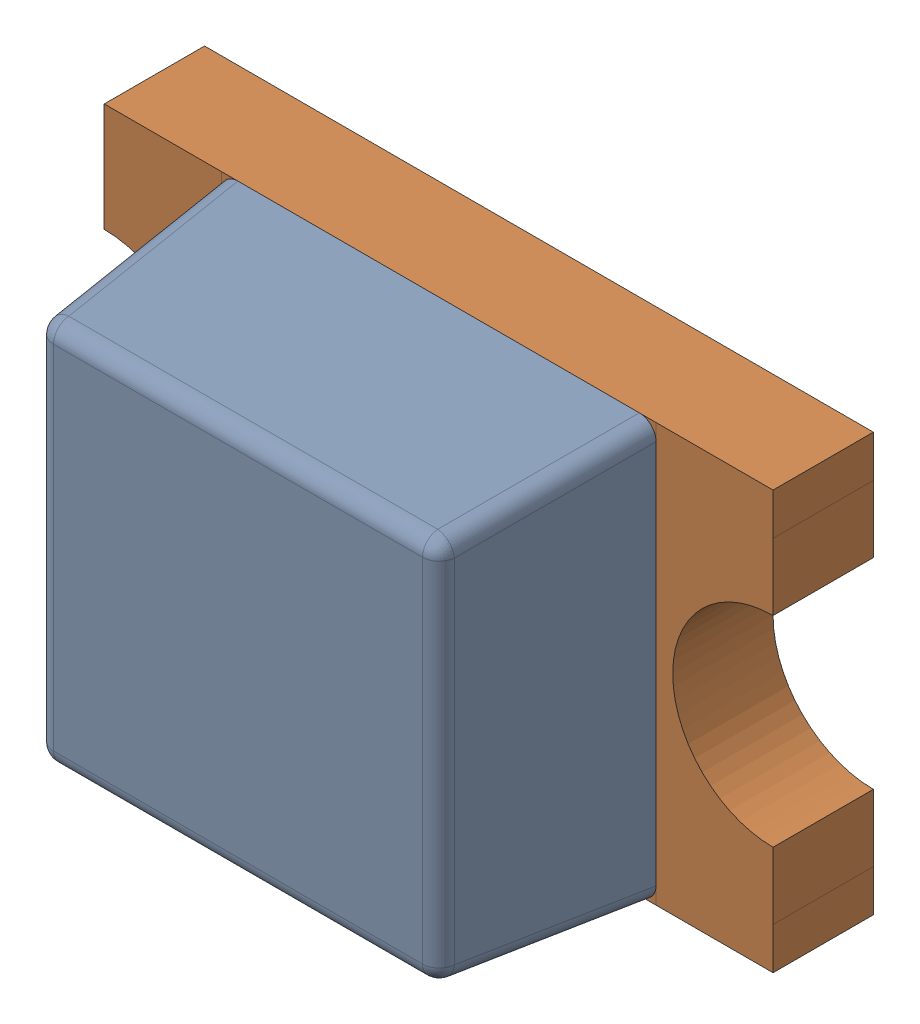
SolidWorks assembly D5_1.step, configuration Default. Lengths in mm.
Overall size (2 1.25 0.9).
2 component instances, 2 part files, 0 mates.
Components (placement in the parent):
- LED 0805 Lens RED_1.step-11: LED 0805 Lens RED_1.step [Default] at (470.1881 335.28 0) x (1 0 0) z (0 -1 0) size (1.3 0.6 1.25)
- LED 0805 Base RED_1.step-11: LED 0805 Base RED_1.step [Default] at (470.1881 335.28 0) x (1 0 0) z (0 -1 0) size (2 0.4 1.25)
